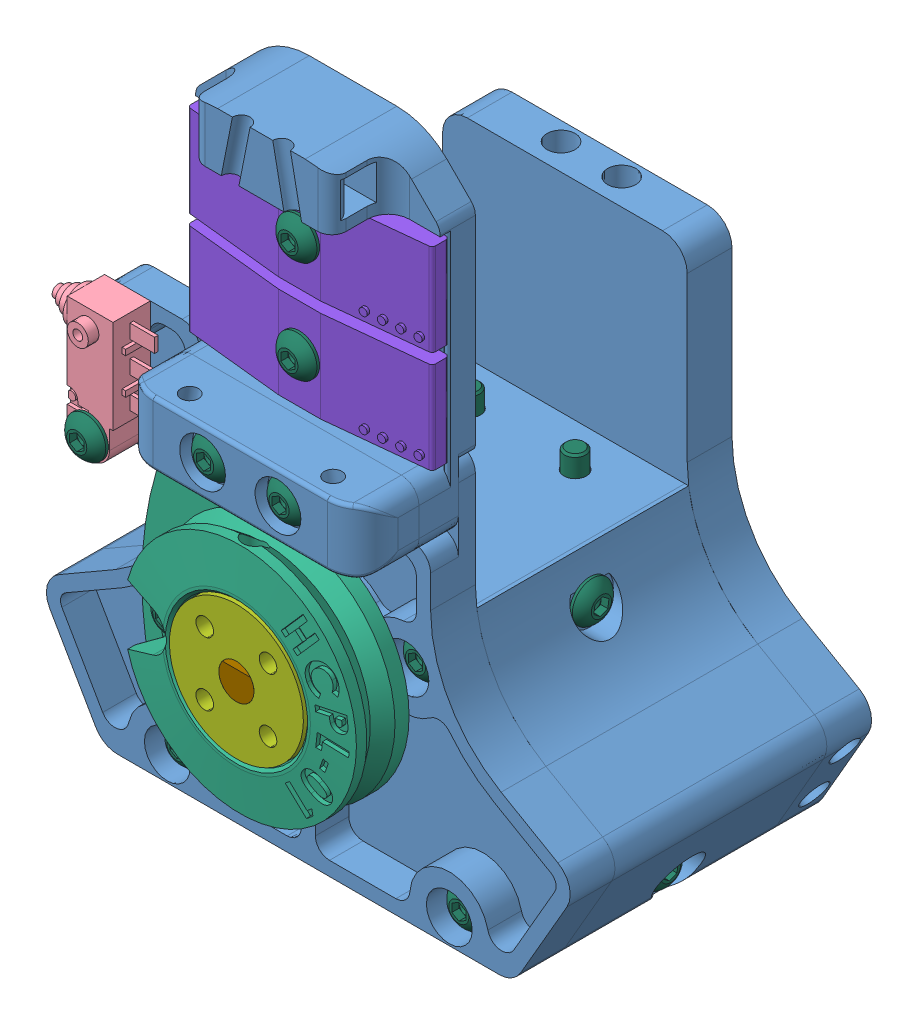
SolidWorks assembly machined_carriage_assembly, configuration 9mm Belts. Lengths in mm.
Overall size (74.31 96.77 62.91).
55 component instances, 17 part files, 104 mates.
Components (placement in the parent):
- machined_carriage-1: machined_carriage [9mm Belts] at origin size (74.31 93.07 52.4)
- 6659K660_OIL-EMBEDDED FLANGED SLEEVE BEARING-1: 6659K660_OIL-EMBEDDED FLANGED SLEEVE BEARING [6659K66] at (0 0 6.35) x (1 0 0) z (0 1 0)
- 6659K660_OIL-EMBEDDED FLANGED SLEEVE BEARING-2: 6659K660_OIL-EMBEDDED FLANGED SLEEVE BEARING [6659K66] at (0 0 -36.4) x (-0.941306 -0.337554 0) z (-0.337554 0.941306 0)
- m3_heat_set_insert_94180A331-1: m3_heat_set_insert_94180A331 [94180A331] at (0 50.25 3.8) x (1 0 0) z (0 -1 0)
- m3_heat_set_insert_94180A331-2: m3_heat_set_insert_94180A331 [94180A331] at (0 35.75 3.8) x (1 0 0) z (0 -1 0)
- m3_heat_set_insert_94180A331-3: m3_heat_set_insert_94180A331 [94180A331] at (5.35 23.95 8) x (1 0 0) z (0 -1 0)
- m3_heat_set_insert_94180A331-4: m3_heat_set_insert_94180A331 [94180A331] at (-5.35 23.95 8) x (1 0 0) z (0 -1 0)
- m3_heat_set_insert_94180A331-5: m3_heat_set_insert_94180A331 [94180A331] at (-13 0 12.35) x (1 0 0) z (0 -1 0)
- D2HW_C201H-1: D2HW_C201H [Default] at (-27.85 25.85 4.4) x (0 -1 0) z (0 0 -1)
- D2HW_C201H-2: D2HW_C201H [Default] at (0 -24.07 -22.6) x (-1 0 0) z (0 0 1)
- 9600K110_SBR RUBBER PUSH-IN GROMMET-1: 9600K110_SBR RUBBER PUSH-IN GROMMET [9600K11] at (-20 -14 0.8063) x (1 0 0) z (0 -1 0)
- carriage_pulley-1: carriage_pulley [Metal Wheel Hub Vairant] at (0 0 8.55) x (0 -1 0) z (-1 0 0)
- hub_5mm_bore-1: hub_5mm_bore [Default] at (0 0 11.55) x (-1 0 0) z (0 1 0)
- belt_clasp-2: belt_clasp [9mm_belt] at (17.35 29.25 3.7) x (-1 0 0) z (0 0 -1) size (34.73 13 3.9)
- belt_clasp-3: belt_clasp [9mm_belt] at (17.35 43.75 3.7) x (-1 0 0) z (0 0 -1) size (34.73 13 3.9)
- twist_lock_assembly-1: twist_lock_assembly [Default] at (97.5575 -375.4795 41.5434) x (-1 0 0) z (0 0 -1) size (31 14.14 154.58)
  - twist_lock_shaft-1: twist_lock_shaft [Default] at (97.5575 375.4795 24.9934) x (0 -1 0) z (-1 0 0) size (5 62.34 5)
  - dowel_pin_3mm_d_12mm_l-1: dowel_pin_3mm_d_12mm_l [91585A371] at (97.5575 375.4795 83.3361) x (-1 0 0) z (0 0.411258 0.911519) size (12 3 3)
  - m3_set_screw_3mm_92015A101-1: m3_set_screw_3mm_92015A101 [92015A101] at (97.5575 375.4795 86.3378) x (0.998583 0.053214 0) z (0 0 1) size (3.46 3.01 3.2)
  - e_clip_98543A103-1: e_clip_98543A103 [98543A103] at (97.5575 375.4795 42.4434) x (0 0 -1) z (0.999491 -0.031891 0) size (0.6 6.9 6.33)
  - m5_shim_0.2mm_thick_98089A246-1: m5_shim_0.2mm_thick_98089A246 [98089A246] at (97.5575 375.4795 42.1434) x (0.716209 -0.697886 0) z (0.697886 0.716209 0) size (10 0.2 10)
  - m5_shim_0.2mm_thick_98089A246-2: m5_shim_0.2mm_thick_98089A246 [98089A246] at (97.5575 375.4795 41.9434) x (0.716209 -0.697886 0) z (0.697886 0.716209 0) size (10 0.2 10)
  - twist_lock_spacer-1: twist_lock_spacer [2.05mm Longer] at (97.5575 375.4795 42.7434) x (-0.145892 -0.989301 0) z (-0.989301 0.145892 0) size (8 28.85 7.95)
- socket button head cap screw_am-1: socket button head cap screw_am [B18.3.4M - 3 x 0.5 x 6 SBHCS --N] at (-13.85 3.5 -35.05) x (0 0 1) z (-1 0 0)
- socket button head cap screw_am-2: socket button head cap screw_am [B18.3.4M - 3 x 0.5 x 6 SBHCS --N] at (13.85 3.5 -35.05) x (0 0 1) z (-1 0 0)
- socket button head cap screw_am-3: socket button head cap screw_am [B18.3.4M - 3 x 0.5 x 6 SBHCS --N] at (-20 -24.07 -35.05) x (0 0 1) z (-1 0 0)
- socket button head cap screw_am-4: socket button head cap screw_am [B18.3.4M - 3 x 0.5 x 6 SBHCS --N] at (20 -24.07 -35.05) x (0 0 1) z (-1 0 0)
- socket button head cap screw_am-5: socket button head cap screw_am [B18.3.4M - 3 x 0.5 x 6 SBHCS --N] at (13.85 3.5 5) x (0 0 -1) z (1 0 0)
- socket button head cap screw_am-6: socket button head cap screw_am [B18.3.4M - 3 x 0.5 x 6 SBHCS --N] at (-13.85 3.5 5) x (0 0 -1) z (1 0 0)
- socket button head cap screw_am-7: socket button head cap screw_am [B18.3.4M - 3 x 0.5 x 6 SBHCS --N] at (-20 -24.07 5) x (0 0 -1) z (1 0 0)
- socket button head cap screw_am-8: socket button head cap screw_am [B18.3.4M - 3 x 0.5 x 6 SBHCS --N] at (20 -24.07 5) x (0 0 -1) z (1 0 0)
- socket button head cap screw_am-9: socket button head cap screw_am [B18.3.4M - 3 x 0.5 x 6 SBHCS --N] at (-20.2 3.5 -15.025)
- socket button head cap screw_am-10: socket button head cap screw_am [B18.3.4M - 3 x 0.5 x 6 SBHCS --N] at (-30 -24.07 -15.025)
- socket button head cap screw_am-11: socket button head cap screw_am [B18.3.4M - 3 x 0.5 x 6 SBHCS --N] at (20.2 3.5 -15.025) x (-1 0 0) z (0 0.924225 0.381849)
- socket button head cap screw_am-12: socket button head cap screw_am [B18.3.4M - 3 x 0.5 x 6 SBHCS --N] at (30 -24.07 -15.025) x (-1 0 0) z (0 0.924225 0.381849)
- socket button head cap screw_am-13: socket button head cap screw_am [B18.3.4M - 3 x 0.5 x 6 SBHCS --N] at (12.55 23.95 7.85) x (0 0 -1) z (1 0 0)
- socket button head cap screw_am-14: socket button head cap screw_am [B18.3.4M - 3 x 0.5 x 6 SBHCS --N] at (-12.55 23.95 7.85) x (0 0 -1) z (1 0 0)
- socket button head cap screw_am-15: socket button head cap screw_am [B18.3.4M - 3 x 0.5 x 12 SBHCS --N] at (5.35 23.95 15.85) x (0 0 -1) z (1 0 0)
- socket button head cap screw_am-16: socket button head cap screw_am [B18.3.4M - 3 x 0.5 x 12 SBHCS --N] at (-5.35 23.95 15.85) x (0 0 -1) z (1 0 0)
- socket button head cap screw_am-18: socket button head cap screw_am [B18.3.4M - 3 x 0.5 x 6 SBHCS --N] at (-7.5 4.675 -24) x (0 1 0) z (0 0 1)
- socket button head cap screw_am-19: socket button head cap screw_am [B18.3.4M - 3 x 0.5 x 8 SBHCS --N] at (-27.85 12.85 11.35) x (0 0 -1) z (1 0 0)
- socket button head cap screw_am-20: socket button head cap screw_am [B18.3.4M - 3 x 0.5 x 4 SBHCS --N] at (-13 0 14) x (0 0 -1) z (1 0 0)
- socket button head cap screw_am-21: socket button head cap screw_am [B18.3.4M - 3 x 0.5 x 6 SBHCS --N] at (0 50.25 9.25) x (0 0 -1) z (1 0 0)
- socket button head cap screw_am-22: socket button head cap screw_am [B18.3.4M - 3 x 0.5 x 6 SBHCS --N] at (0 35.75 9.25) x (0 0 -1) z (1 0 0)
- socket button head cap screw_am-23: socket button head cap screw_am [B18.3.4M - 3 x 0.5 x 6 SBHCS --N] at (7.5 4.675 -24) x (0 1 0) z (0 0 1)
- socket button head cap screw_am-24: socket button head cap screw_am [B18.3.4M - 3 x 0.5 x 6 SBHCS --N] at (7.5 4.675 -4) x (0 1 0) z (0 0 1)
- socket button head cap screw_am-25: socket button head cap screw_am [B18.3.4M - 3 x 0.5 x 6 SBHCS --N] at (-7.5 4.675 -4) x (0 1 0) z (0 0 1)
- socket button head cap screw_am-26: socket button head cap screw_am [B18.3.4M - 3 x 0.5 x 8 SBHCS --N] at (-13 -24.07 -29.55) x (0 0 1) z (-1 0 0)
- m3_set_screw_8mm_91390A101-1: m3_set_screw_8mm_91390A101 [91390A101] at (0 5.7469 14.05) x (1 0 0) z (0 1 0)
- 94128A105_ HEADLESS SHOULDER SCREWS-1: 94128A105_ HEADLESS SHOULDER SCREWS [94128A105] at (4.3 28 -33.8) x (1 0 0) z (0 -1 0)
- 94128A105_ HEADLESS SHOULDER SCREWS-2: 94128A105_ HEADLESS SHOULDER SCREWS [94128A105] at (-4.3 28 -33.8) x (1 0 0) z (0 -1 0)
- 94128A105_ HEADLESS SHOULDER SCREWS-3: 94128A105_ HEADLESS SHOULDER SCREWS [94128A105] at (26.3979 -10.2761 -33.8) x (-0.5 -0.866025 0) z (-0.866025 0.5 0)
- 94128A105_ HEADLESS SHOULDER SCREWS-4: 94128A105_ HEADLESS SHOULDER SCREWS [94128A105] at (22.0979 -17.7239 -33.8) x (-0.5 -0.866025 0) z (-0.866025 0.5 0)
- 94128A105_ HEADLESS SHOULDER SCREWS-5: 94128A105_ HEADLESS SHOULDER SCREWS [94128A105] at (-26.3979 -10.2761 -33.8) x (-0.5 0.866025 0) z (0.866025 0.5 0)
- 94128A105_ HEADLESS SHOULDER SCREWS-6: 94128A105_ HEADLESS SHOULDER SCREWS [94128A105] at (-22.0979 -17.7239 -33.8) x (-0.5 0.866025 0) z (0.866025 0.5 0)
Mates (geometry in assembly coordinates):
- Concentric1: concentric aligned: cylinder of machined_carriage-1 through (0 0 1.15) axis (0 0 1) radius 4; cylinder of 6659K660_OIL-EMBEDDED FLANGED SLEEVE BEARING-1 through (0 0 1.35) axis (0 0 1) radius 4.01
- Coincident1: coincident anti-aligned: plane of machined_carriage-1 through (0 0 4.85) normal (0 0 1); plane of 6659K660_OIL-EMBEDDED FLANGED SLEEVE BEARING-1 through (0 0 4.85) normal (0 0 -1)
- Concentric2: concentric aligned: cylinder of machined_carriage-1 through (0 0 -31.2) axis (0 0 -1) radius 4; cylinder of 6659K660_OIL-EMBEDDED FLANGED SLEEVE BEARING-2 through (0 0 -31.4) axis (0 0 -1) radius 4.01
- Coincident2: coincident anti-aligned: plane of machined_carriage-1 through (0 0 -34.9) normal (0 0 -1); plane of 6659K660_OIL-EMBEDDED FLANGED SLEEVE BEARING-2 through (0 0 -34.9) normal (0 0 1)
- Concentric3: concentric aligned: cylinder of machined_carriage-1 through (-13.85 3.5 -36.4) axis (0 0 -1) radius 1.6; cylinder of socket button head cap screw_am-1 through (-13.85 3.5 -35.05) axis (0 0 -1) radius 2.85
- Coincident3: coincident anti-aligned: plane of machined_carriage-1 through (-12.25 3.5 -33.4) normal (0 0 -1); plane of socket button head cap screw_am-1 through (-13.85 5 -33.4) normal (0 0 1)
- Concentric4: concentric aligned: cylinder of machined_carriage-1 through (13.85 3.5 -36.4) axis (0 0 -1) radius 1.6; cylinder of socket button head cap screw_am-2 through (13.85 3.5 -35.05) axis (0 0 -1) radius 2.85
- Coincident4: coincident anti-aligned: plane of machined_carriage-1 through (15.45 3.5 -33.4) normal (0 0 -1); plane of socket button head cap screw_am-2 through (13.85 5 -33.4) normal (0 0 1)
- Concentric5: concentric aligned: cylinder of machined_carriage-1 through (-20 -24.07 -36.4) axis (0 0 -1) radius 1.6; cylinder of socket button head cap screw_am-3 through (-20 -24.07 -35.05) axis (0 0 -1) radius 2.85
- Coincident5: coincident anti-aligned: plane of machined_carriage-1 through (-18.4 -24.07 -33.4) normal (0 0 -1); plane of socket button head cap screw_am-3 through (-20 -22.57 -33.4) normal (0 0 1)
- Concentric6: concentric aligned: cylinder of machined_carriage-1 through (20 -24.07 -36.4) axis (0 0 -1) radius 1.6; cylinder of socket button head cap screw_am-4 through (20 -24.07 -35.05) axis (0 0 -1) radius 2.85
- Coincident6: coincident anti-aligned: plane of machined_carriage-1 through (21.6 -24.07 -33.4) normal (0 0 -1); plane of socket button head cap screw_am-4 through (20 -22.57 -33.4) normal (0 0 1)
- Concentric7: concentric aligned: cylinder of machined_carriage-1 through (13.85 3.5 0) axis (0 0 1) radius 1.6; cylinder of socket button head cap screw_am-5 through (13.85 3.5 5) axis (0 0 1) radius 2.85
- Coincident7: coincident anti-aligned: plane of machined_carriage-1 through (15.4375 3.5 3.35) normal (0 0 1); plane of socket button head cap screw_am-5 through (13.85 5 3.35) normal (0 0 -1)
- Concentric8: concentric aligned: cylinder of machined_carriage-1 through (-13.85 3.5 0) axis (0 0 1) radius 1.6; cylinder of socket button head cap screw_am-6 through (-13.85 3.5 5) axis (0 0 1) radius 2.85
- Coincident8: coincident anti-aligned: plane of machined_carriage-1 through (-12.2625 3.5 3.35) normal (0 0 1); plane of socket button head cap screw_am-6 through (-13.85 5 3.35) normal (0 0 -1)
- Concentric9: concentric aligned: cylinder of machined_carriage-1 through (-20 -24.07 0) axis (0 0 1) radius 1.6; cylinder of socket button head cap screw_am-7 through (-20 -24.07 5) axis (0 0 1) radius 2.85
- Coincident9: coincident anti-aligned: plane of machined_carriage-1 through (-18.4125 -24.07 3.35) normal (0 0 1); plane of socket button head cap screw_am-7 through (-20 -22.57 3.35) normal (0 0 -1)
- Concentric10: concentric aligned: cylinder of machined_carriage-1 through (20 -24.07 0) axis (0 0 1) radius 1.6; cylinder of socket button head cap screw_am-8 through (20 -24.07 5) axis (0 0 1) radius 2.85
- Coincident10: coincident anti-aligned: plane of machined_carriage-1 through (21.5875 -24.07 3.35) normal (0 0 1); plane of socket button head cap screw_am-8 through (20 -22.57 3.35) normal (0 0 -1)
- Concentric11: concentric aligned: cylinder of machined_carriage-1 through (37.1556 3.5 -15.025) axis (-1 0 0) radius 1.6; cylinder of socket button head cap screw_am-9 through (-20.2 3.5 -15.025) axis (-1 0 0) radius 2.85
- Coincident11: coincident anti-aligned: plane of machined_carriage-1 through (-18.55 3.5 -15.025) normal (-1 0 0); plane of socket button head cap screw_am-9 through (-18.55 5 -15.025) normal (1 0 0)
- Concentric12: concentric aligned: cylinder of machined_carriage-1 through (37.1556 -24.07 -15.025) axis (-1 0 0) radius 1.6; cylinder of socket button head cap screw_am-10 through (-30 -24.07 -15.025) axis (-1 0 0) radius 2.85
- Coincident12: coincident anti-aligned: plane of machined_carriage-1 through (-28.35 -24.07 -15.025) normal (-1 0 0); plane of socket button head cap screw_am-10 through (-28.35 -22.57 -15.025) normal (1 0 0)
- Concentric13: concentric aligned: cylinder of machined_carriage-1 through (-37.1556 3.5 -15.025) axis (1 0 0) radius 1.6; cylinder of socket button head cap screw_am-11 through (20.2 3.5 -15.025) axis (1 0 0) radius 2.85
- Coincident13: coincident anti-aligned: plane of machined_carriage-1 through (18.55 3.5 -15.025) normal (1 0 0); plane of socket button head cap screw_am-11 through (18.55 2.9272 -13.6387) normal (-1 0 0)
- Concentric14: concentric aligned: cylinder of machined_carriage-1 through (-37.1556 -24.07 -15.025) axis (1 0 0) radius 1.6; cylinder of socket button head cap screw_am-12 through (30 -24.07 -15.025) axis (1 0 0) radius 2.85
- Coincident14: coincident anti-aligned: plane of machined_carriage-1 through (28.35 -24.07 -15.025) normal (1 0 0); plane of socket button head cap screw_am-12 through (28.35 -24.6428 -13.6387) normal (-1 0 0)
- Concentric15: concentric aligned: cylinder of machined_carriage-1 through (12.55 23.95 8) axis (0 0 1) radius 1.6; cylinder of socket button head cap screw_am-13 through (12.55 23.95 7.85) axis (0 0 1) radius 2.85
- Coincident15: coincident anti-aligned: plane of machined_carriage-1 through (14.15 23.95 6.2) normal (0 0 1); plane of socket button head cap screw_am-13 through (12.55 25.45 6.2) normal (0 0 -1)
- Concentric16: concentric aligned: cylinder of machined_carriage-1 through (-12.55 23.95 8) axis (0 0 1) radius 1.6; cylinder of socket button head cap screw_am-14 through (-12.55 23.95 7.85) axis (0 0 1) radius 2.85
- Coincident16: coincident anti-aligned: plane of machined_carriage-1 through (-10.95 23.95 6.2) normal (0 0 1); plane of socket button head cap screw_am-14 through (-12.55 25.45 6.2) normal (0 0 -1)
- Concentric17: concentric aligned: cylinder of machined_carriage-1 through (0 50.25 0) axis (0 0 1) radius 2.525; cylinder of m3_heat_set_insert_94180A331-1 through (0 50.25 3.546) axis (0 0 1) radius 2.78
- Coincident17: coincident aligned: plane of machined_carriage-1 through (15.35 57.67 3.8) normal (0 0 1); plane of m3_heat_set_insert_94180A331-1 through (0 50.25 3.8) normal (0 0 1)
- Concentric18: concentric aligned: cylinder of machined_carriage-1 through (0 35.75 0) axis (0 0 1) radius 2.525; cylinder of m3_heat_set_insert_94180A331-2 through (0 35.75 3.546) axis (0 0 1) radius 2.78
- Coincident18: coincident aligned: plane of machined_carriage-1 through (15.35 57.67 3.8) normal (0 0 1); plane of m3_heat_set_insert_94180A331-2 through (0 35.75 3.8) normal (0 0 1)
- Concentric19: concentric anti-aligned: cylinder of machined_carriage-1 through (5.35 23.95 5) axis (0 0 -1) radius 2.525; cylinder of m3_heat_set_insert_94180A331-3 through (5.35 23.95 7.746) axis (0 0 1) radius 2.78
- Coincident19: coincident aligned: plane of machined_carriage-1 through (15.35 57.67 8) normal (0 0 1); plane of m3_heat_set_insert_94180A331-3 through (5.35 23.95 8) normal (0 0 1)
- Concentric20: concentric anti-aligned: cylinder of machined_carriage-1 through (-5.35 23.95 5) axis (0 0 -1) radius 2.525; cylinder of m3_heat_set_insert_94180A331-4 through (-5.35 23.95 7.746) axis (0 0 1) radius 2.78
- Coincident20: coincident aligned: plane of machined_carriage-1 through (15.35 57.67 8) normal (0 0 1); plane of m3_heat_set_insert_94180A331-4 through (-5.35 23.95 8) normal (0 0 1)
- Concentric21: concentric anti-aligned: cylinder of machined_carriage-1 through (5.35 23.95 16) axis (0 0 -1) radius 1.6; cylinder of socket button head cap screw_am-15 through (5.35 23.95 15.85) axis (0 0 1) radius 2.85
- Coincident21: coincident anti-aligned: plane of machined_carriage-1 through (5.35 23.95 14.2) normal (0 0 1); plane of socket button head cap screw_am-15 through (5.35 25.45 14.2) normal (0 0 -1)
- Concentric22: concentric anti-aligned: cylinder of machined_carriage-1 through (-5.35 23.95 16) axis (0 0 -1) radius 1.6; cylinder of socket button head cap screw_am-16 through (-5.35 23.95 15.85) axis (0 0 1) radius 2.85
- Coincident22: coincident anti-aligned: plane of machined_carriage-1 through (-5.35 23.95 14.2) normal (0 0 1); plane of socket button head cap screw_am-16 through (-5.35 25.45 14.2) normal (0 0 -1)
- Coincident23: coincident anti-aligned: plane of machined_carriage-1 through (0 0 4.4) normal (0 0 1); plane of D2HW_C201H-1 through (-24.35 28.5 4.4) normal (0 0 -1)
- Concentric23: concentric aligned: cylinder of machined_carriage-1 through (-27.85 25.85 0) axis (0 0 1) radius 1.5875; cylinder of D2HW_C201H-1 through (-27.85 25.85 2.9) axis (0 0 1) radius 1.5
- Coincident24: coincident aligned: plane of machined_carriage-1 through (-30.85 28.5 4.4) normal (-1 0 0); plane of D2HW_C201H-1 through (-30.85 28.5 9.7) normal (-1 0 0)
- Concentric24: concentric anti-aligned: cylinder of 6659K660_OIL-EMBEDDED FLANGED SLEEVE BEARING-2 through (0 0 -31.4) axis (0 0 -1) radius 2.5; cylinder of twist_lock_assembly-1/twist_lock_shaft-1 through (0 0 -45.7926) axis (0 0 1) radius 2.5
- Coincident26: coincident anti-aligned: plane of machined_carriage-1 through (-37.35 12.2936 -30.05) normal (0 0 1); plane of twist_lock_assembly-1/twist_lock_spacer-1 through (0 0 -30.05) normal (0 0 -1)
- Concentric26: concentric aligned: cylinder of machined_carriage-1 through (-7.5 0.325 -24) axis (0 -1 0) radius 1.6; cylinder of socket button head cap screw_am-18 through (-7.5 4.675 -24) axis (0 -1 0) radius 2.85
- Coincident27: coincident anti-aligned: plane of machined_carriage-1 through (-5.9 6.325 -24) normal (0 -1 0); plane of socket button head cap screw_am-18 through (-9 6.325 -24) normal (0 1 0)
- Concentric28: concentric aligned: cylinder of machined_carriage-1 through (-27.85 12.85 0) axis (0 0 1) radius 1.25; cylinder of socket button head cap screw_am-19 through (-27.85 12.85 11.35) axis (0 0 1) radius 2.85
- Coincident29: coincident anti-aligned: plane of D2HW_C201H-1 through (-24.35 28.5 9.7) normal (0 0 1); plane of socket button head cap screw_am-19 through (-27.85 14.35 9.7) normal (0 0 -1)
- Concentric29: concentric aligned: cylinder of machined_carriage-1 through (4.3 20.0931 -33.8) axis (0 1 0) radius 2; cylinder of 94128A105_ HEADLESS SHOULDER SCREWS-1 through (4.3 34.25 -33.8) axis (0 1 0) radius 2
- Coincident30: coincident anti-aligned: plane of machined_carriage-1 through (6 26.25 -33.47) normal (0 1 0); plane of 94128A105_ HEADLESS SHOULDER SCREWS-1 through (4.3 26.25 -32.3) normal (0 -1 0)
- Concentric30: concentric aligned: cylinder of machined_carriage-1 through (-4.3 20.0931 -33.8) axis (0 1 0) radius 2; cylinder of 94128A105_ HEADLESS SHOULDER SCREWS-2 through (-4.3 34.25 -33.8) axis (0 1 0) radius 2
- Coincident31: coincident anti-aligned: plane of machined_carriage-1 through (6 26.25 -33.47) normal (0 1 0); plane of 94128A105_ HEADLESS SHOULDER SCREWS-2 through (-4.3 26.25 -32.3) normal (0 -1 0)
- Concentric32: concentric aligned: cylinder of machined_carriage-1 through (19.5504 -6.3227 -33.8) axis (0.866025 -0.5 0) radius 2; cylinder of 94128A105_ HEADLESS SHOULDER SCREWS-3 through (31.8106 -13.4011 -33.8) axis (0.866025 -0.5 0) radius 2
- Parallel1: parallel aligned: plane of machined_carriage-1 through (-37.35 12.2936 -36.4) normal (0 0 -1); plane of 94128A105_ HEADLESS SHOULDER SCREWS-3 through (29.9446 -14.6331 -33.55) normal (0 0 -1)
- Coincident33: coincident anti-aligned: plane of machined_carriage-1 through (19.7324 -18.3212 -33.47) normal (0.866025 -0.5 0); plane of 94128A105_ HEADLESS SHOULDER SCREWS-3 through (24.8824 -9.4011 -32.3) normal (-0.866025 0.5 0)
- Concentric33: concentric aligned: cylinder of machined_carriage-1 through (15.2504 -13.7705 -33.8) axis (0.866025 -0.5 0) radius 2; cylinder of 94128A105_ HEADLESS SHOULDER SCREWS-4 through (27.5106 -20.8489 -33.8) axis (0.866025 -0.5 0) radius 2
- Parallel2: parallel aligned: plane of machined_carriage-1 through (-37.35 12.2936 -36.4) normal (0 0 -1); plane of 94128A105_ HEADLESS SHOULDER SCREWS-4 through (25.6446 -22.081 -33.55) normal (0 0 -1)
- Coincident35: coincident anti-aligned: plane of machined_carriage-1 through (19.7324 -18.3212 -33.47) normal (0.866025 -0.5 0); plane of 94128A105_ HEADLESS SHOULDER SCREWS-4 through (20.5824 -16.8489 -32.3) normal (-0.866025 0.5 0)
- Concentric34: concentric aligned: cylinder of machined_carriage-1 through (-19.5504 -6.3227 -33.8) axis (-0.866025 -0.5 0) radius 2; cylinder of 94128A105_ HEADLESS SHOULDER SCREWS-5 through (-31.8106 -13.4011 -33.8) axis (-0.866025 -0.5 0) radius 2
- Parallel3: parallel aligned: plane of machined_carriage-1 through (-37.35 12.2936 -36.4) normal (0 0 -1); plane of 94128A105_ HEADLESS SHOULDER SCREWS-5 through (-31.9446 -11.169 -33.55) normal (0 0 -1)
- Coincident37: coincident anti-aligned: plane of machined_carriage-1 through (-19.7324 -18.3212 -33.47) normal (-0.866025 -0.5 0); plane of 94128A105_ HEADLESS SHOULDER SCREWS-5 through (-24.8824 -9.4011 -32.3) normal (0.866025 0.5 0)
- Concentric35: concentric aligned: cylinder of machined_carriage-1 through (-15.2504 -13.7705 -33.8) axis (-0.866025 -0.5 0) radius 2; cylinder of 94128A105_ HEADLESS SHOULDER SCREWS-6 through (-27.5106 -20.8489 -33.8) axis (-0.866025 -0.5 0) radius 2
- Parallel4: parallel aligned: plane of machined_carriage-1 through (-37.35 12.2936 -36.4) normal (0 0 -1); plane of 94128A105_ HEADLESS SHOULDER SCREWS-6 through (-27.6446 -18.6169 -33.55) normal (0 0 -1)
- Coincident39: coincident anti-aligned: plane of machined_carriage-1 through (-19.7324 -18.3212 -33.47) normal (-0.866025 -0.5 0); plane of 94128A105_ HEADLESS SHOULDER SCREWS-6 through (-20.5824 -16.8489 -32.3) normal (0.866025 0.5 0)
- Concentric36: concentric anti-aligned: cylinder of machined_carriage-1 through (-20 -14 -13.9516) axis (0 0 1) radius 3.175; cylinder of 9600K110_SBR RUBBER PUSH-IN GROMMET-1 through (-20 -14 -1.9719) axis (0 0 -1) radius 3.175
- Coincident40: coincident anti-aligned: plane of machined_carriage-1 through (-15.35 49.27 1.6) normal (0 0 1); plane of 9600K110_SBR RUBBER PUSH-IN GROMMET-1 through (-20 -17.175 1.6) normal (0 0 -1)
- Coincident42: coincident anti-aligned: plane of carriage_pulley-1 through (0 0 11.55) normal (0 0 1); plane of hub_5mm_bore-1 through (0 0 11.55) normal (0 0 -1)
- Concentric38: concentric anti-aligned: cylinder of carriage_pulley-1 through (0 0 16.551) axis (0 0 -1) radius 2.575; cylinder of hub_5mm_bore-1 through (0 0 16.55) axis (0 0 1) radius 2.5
- Concentric39: concentric anti-aligned: cylinder of carriage_pulley-1 through (0 19.4 14.05) axis (0 -1 0) radius 1.6; cylinder of hub_5mm_bore-1 through (0 9.5 14.05) axis (0 1 0) radius 1.25
- Concentric40: concentric aligned: cylinder of twist_lock_assembly-1/twist_lock_shaft-1 through (0 0 -45.7926) axis (0 0 1) radius 2.5; cylinder of hub_5mm_bore-1 through (0 0 16.55) axis (0 0 1) radius 2.5
- Coincident43: coincident aligned: plane of twist_lock_assembly-1/twist_lock_shaft-1 through (0 0 16.55) normal (0 0 1); plane of hub_5mm_bore-1 through (0 0 16.55) normal (0 0 1)
- Concentric41: concentric aligned: cylinder of hub_5mm_bore-1 through (0 9.5 14.05) axis (0 1 0) radius 1.25; circle of m3_set_screw_8mm_91390A101-1
- Coincident44: coincident aligned: plane of twist_lock_assembly-1/twist_lock_shaft-1 through (-2.5 1.5 16.55) normal (0 1 0); circle of m3_set_screw_8mm_91390A101-1
- LimitAngle1: limit planar angle = 3.141593 rad aligned: plane of twist_lock_assembly-1/twist_lock_shaft-1 through (-2.5 1.5 16.55) normal (0 1 0); plane of machined_carriage-1 through (-14.85 19.45 16) normal (0 -1 0)
- Concentric42: concentric anti-aligned: cylinder of carriage_pulley-1 through (-13 0 19.5625) axis (0 0 -1) radius 2.55; cylinder of m3_heat_set_insert_94180A331-5 through (-13 0 12.096) axis (0 0 1) radius 2.78
- Coincident46: coincident aligned: plane of carriage_pulley-1 through (0 0 12.35) normal (0 0 1); plane of m3_heat_set_insert_94180A331-5 through (-13 0 12.35) normal (0 0 1)
- Concentric43: concentric anti-aligned: cone of m3_heat_set_insert_94180A331-5 through (-13 0 11.975) axis (0 0 -1); cylinder of socket button head cap screw_am-20 through (-13 0 14) axis (0 0 1) radius 2.85
- Coincident47: coincident anti-aligned: plane of m3_heat_set_insert_94180A331-5 through (-13 0 12.35) normal (0 0 1); plane of socket button head cap screw_am-20 through (-13 1.5 12.35) normal (0 0 -1)
- Concentric44: concentric aligned: circle of machined_carriage-1; cylinder of belt_clasp-2 through (0 35.75 3.7035) axis (0 0 1) radius 1.6
- Parallel6: parallel aligned: plane of machined_carriage-1 through (14.85 28.5 16) normal (0 1 0); plane of belt_clasp-2 through (17.35 42.25 3.7) normal (0 1 0)
- Coincident49: coincident anti-aligned: plane of machined_carriage-1 through (15.35 57.67 3.8) normal (0 0 1); plane of belt_clasp-2 through (-3 42.25 3.8) normal (0 0 -1)
- Concentric45: concentric aligned: circle of m3_heat_set_insert_94180A331-1; cylinder of belt_clasp-3 through (0 50.25 3.7035) axis (0 0 1) radius 1.6
- Parallel7: parallel aligned: plane of machined_carriage-1 through (14.85 28.5 16) normal (0 1 0); plane of belt_clasp-3 through (17.35 56.75 3.7) normal (0 1 0)
- Coincident51: coincident anti-aligned: plane of machined_carriage-1 through (15.35 57.67 3.8) normal (0 0 1); plane of belt_clasp-3 through (-3 56.75 3.8) normal (0 0 -1)
- Concentric46: concentric aligned: cylinder of belt_clasp-3 through (0 50.25 3.7035) axis (0 0 1) radius 1.6; cylinder of socket button head cap screw_am-21 through (0 50.25 9.25) axis (0 0 1) radius 2.85
- Coincident52: coincident anti-aligned: plane of belt_clasp-3 through (-3 56.75 7.6) normal (0 0 1); plane of socket button head cap screw_am-21 through (0 51.75 7.6) normal (0 0 -1)
- Concentric47: concentric aligned: cylinder of belt_clasp-2 through (0 35.75 3.7035) axis (0 0 1) radius 1.6; cylinder of socket button head cap screw_am-22 through (0 35.75 9.25) axis (0 0 1) radius 2.85
- Coincident53: coincident anti-aligned: plane of belt_clasp-2 through (-3 42.25 7.6) normal (0 0 1); plane of socket button head cap screw_am-22 through (0 37.25 7.6) normal (0 0 -1)
- Concentric48: concentric aligned: cylinder of machined_carriage-1 through (7.5 0.325 -24) axis (0 -1 0) radius 1.6; cylinder of socket button head cap screw_am-23 through (7.5 4.675 -24) axis (0 -1 0) radius 2.85
- Coincident54: coincident anti-aligned: plane of machined_carriage-1 through (9.1 6.325 -24) normal (0 -1 0); plane of socket button head cap screw_am-23 through (6 6.325 -24) normal (0 1 0)
- Concentric49: concentric aligned: cylinder of machined_carriage-1 through (7.5 0.325 -4) axis (0 -1 0) radius 1.6; cylinder of socket button head cap screw_am-24 through (7.5 4.675 -4) axis (0 -1 0) radius 2.85
- Coincident55: coincident anti-aligned: plane of machined_carriage-1 through (9.1 6.325 -4) normal (0 -1 0); plane of socket button head cap screw_am-24 through (6 6.325 -4) normal (0 1 0)
- Concentric50: concentric aligned: cylinder of machined_carriage-1 through (-7.5 0.325 -4) axis (0 -1 0) radius 1.6; cylinder of socket button head cap screw_am-25 through (-7.5 4.675 -4) axis (0 -1 0) radius 2.85
- Coincident56: coincident anti-aligned: plane of machined_carriage-1 through (-5.9 6.325 -4) normal (0 -1 0); plane of socket button head cap screw_am-25 through (-9 6.325 -4) normal (0 1 0)
- Coincident57: coincident anti-aligned: plane of machined_carriage-1 through (-16.1 65.501 -22.6) normal (0 0 -1); plane of D2HW_C201H-2 through (2.65 -20.57 -22.6) normal (0 0 1)
- Concentric51: concentric aligned: cylinder of machined_carriage-1 through (0 -24.07 -20.6) axis (0 0 -1) radius 1.5; cylinder of D2HW_C201H-2 through (0 -24.07 -21.1) axis (0 0 -1) radius 1.5
- Parallel10: parallel aligned: plane of machined_carriage-1 through (23.175 -27.245 -30.05) normal (0 -1 0); plane of D2HW_C201H-2 through (2.65 -27.07 -27.9) normal (0 -1 0)
- Concentric52: concentric aligned: cylinder of machined_carriage-1 through (-13 -24.07 -22.6) axis (0 0 -1) radius 1.25; cylinder of socket button head cap screw_am-26 through (-13 -24.07 -29.55) axis (0 0 -1) radius 2.85
- Coincident62: coincident anti-aligned: plane of D2HW_C201H-2 through (2.65 -20.57 -27.9) normal (0 0 -1); plane of socket button head cap screw_am-26 through (-13 -22.57 -27.9) normal (0 0 1)
